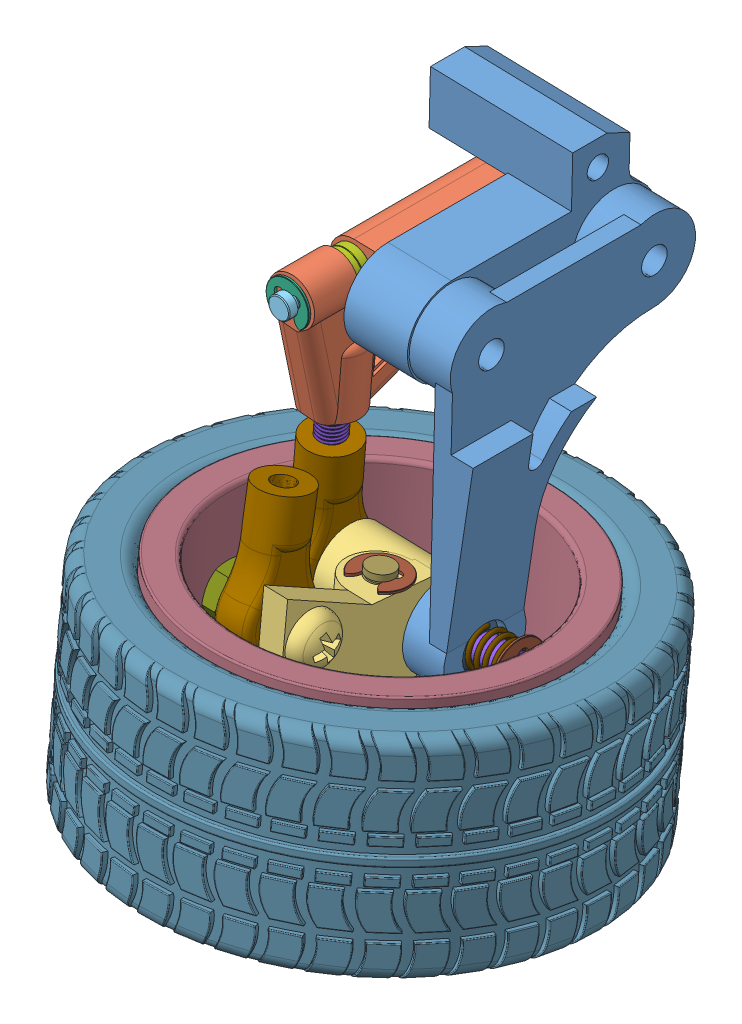
SolidWorks assembly 左前轮, configuration 默认. Lengths in mm.
35 component instances, 21 part files, 72 mates.
Components (placement in the parent):
- 前轮悬挂固定座-左-1: 前轮悬挂固定座-左 [默认] at (-4.1748 40.7369 44.8092) x (0 0 -1) z (-0.999668 0.025755 0) size (28.6 39.6 7.4)
- 前轮悬挂支撑臂-1: 前轮悬挂支撑臂 [默认] at (-19.3996 40.1041 44.6092) x (0 0 -1) z (-0.996802 0.079912 0) size (31.32 16.5 6)
- 转向摇臂-左-1: 转向摇臂-左 [默认] at (-10.8363 10.8664 44.7682) x (0.017235 0.996497 -0.081837) z (-0.999795 0.016302 -0.012048) size (14.2 22.2 10.13)
- 沉头螺钉-M3-1: 沉头螺钉-M3 [GB_WOOD_SCREWS_TYPE135 3X8-C] at (-13.5443 34.2761 39.8092) x (0.025755 0.999668 0) z (-0.463299 0.011936 0.886122) size (8.5 6 6)
- 沉头螺钉-M3-2: 沉头螺钉-M3 [GB_WOOD_SCREWS_TYPE135 3X8-C] at (-13.5443 34.2761 29.8092) x (0.025755 0.999668 0) z (0 0 1) size (8.5 6 6)
- 悬挂销钉-M2.5-1: 悬挂销钉-M2.5 [默认] at (-21.6922 40.2879 18.1092) size (2.5 2.5 34)
- 挡圈-M2.5-1: 挡圈-M2.5 [默认] at (-21.6922 40.2879 19.4092) x (-0.923728 -0.383049 0) z (0 0 -1) size (5 4.5 0.3)
- 挡圈-M2.5-2: 挡圈-M2.5 [默认] at (-21.6922 40.2879 50.8092) size (5 4.5 0.3)
- 垫片-M3-2: 垫片-M3 [默认] at (-21.6922 40.2879 43.4092) size (4.5 4.5 1)
- 垫片-M3-3: 垫片-M3 [默认] at (-21.6922 40.2879 44.4092) size (4.5 4.5 1)
- 垫片-M3-4: 垫片-M3 [默认] at (-21.6922 40.2879 25.1092) x (0.996807 -0.079852 0) z (0 0 1) size (4.5 4.5 1)
- 悬挂销钉-M3-1: 悬挂销钉-M3 [默认] at (-27.5329 11.1387 44.567) x (-0.007064 0.2769 0.960873) z (0.999795 -0.016302 0.012048) size (3 3 27.5)
- 前拉杆球头-1: 前拉杆球头 [默认] at (-24.0336 11.0816 44.6092) x (-0.079912 -0.996802 0) z (0 0 1) size (16.5 5.82 9)
- 半球型活动头-1: 半球型活动头 [默认] at (-24.0567 11.7504 47.4309) x (0.007965 -0.230623 -0.973011) z (-0.018641 -0.972907 0.230446) size (5.8 4.8 5.8)
- 挡圈-M3-1: 挡圈-M3 [默认] at (-26.7331 11.1256 44.5767) x (0.019643 0.925969 -0.377089) z (0.999795 -0.016302 0.012048) size (6 5.32 0.3)
- 挡圈-M3-2: 挡圈-M3 [默认] at (-1.1383 10.7083 44.8851) x (0.019537 0.616444 -0.787156) z (0.999795 -0.016302 0.012048) size (6 5.32 0.3)
- 垫片-M3-5: 垫片-M3 [默认] at (-20.6343 11.0262 44.6501) x (-0.007721 0.243313 0.969917) z (-0.999795 0.016302 -0.012048) size (4.5 4.5 1)
- 半球型活动头-2: 半球型活动头 [默认] at (-7.4714 10.8468 47.7088) x (0.011847 -0.012367 -0.999853) z (0.016449 0.999791 -0.012172) size (5.8 4.8 5.8)
- 垫片-M3-6: 垫片-M3 [默认] at (-9.8366 10.8501 44.7803) x (-0.014725 -0.175564 0.984358) z (-0.999795 0.016302 -0.012048) size (4.5 4.5 1)
- 前轮轴-1: 前轮轴 [默认] at (-13.6492 12.9342 48.5817) x (-0.911466 0.049305 0.408411) z (0.017235 0.996497 -0.081837) size (4.6 4.19 25.74)
- 挡圈-M3-3: 挡圈-M3 [默认] at (-13.6043 15.5251 48.3689) x (0.998548 -0.021333 -0.049473) z (0.017235 0.996497 -0.081837) size (6 5.32 0.3)
- 轮毂-前轮-1: 轮毂-前轮 [默认] at (-14.0076 -7.7929 50.2839) x (0.552508 -0.077709 -0.829877) z (0.833329 0.030913 0.551912) size (40 26.36 40)
- 橡胶胎-1: 橡胶胎 [默认] at (-14.0111 -7.9922 50.3002) x (0.552508 -0.077709 -0.829877) z (0.833329 0.030913 0.551912) size (52.2 24.12 52.2)
- 深沟轴承-M7-1: 深沟轴承-M7 [Rolling bearings 618-3 GB 276-94] at (-13.8215 2.9692 49.4) x (-0.017235 -0.996497 0.081837) z (0.158761 0.078083 0.984224) size (2 7 7)
- 深沟轴承-M7-2: 深沟轴承-M7 [Rolling bearings 618-3 GB 276-94] at (-13.9594 -5.0027 50.0547) x (0.017235 0.996497 -0.081837) z (0.833329 0.030913 0.551912) size (2 7 7)
- 六角螺母-M3-2: 六角螺母-M3 [GB_FASTENER_NUT_SNAB1 M3-C] at (-13.9766 -5.9992 50.1366) x (0.998548 -0.021333 -0.049473) z (0.017235 0.996497 -0.081837) size (6.35 5.5 2.4)
- 丝杆-1: 丝杆 [默认] at (-22.3555 32.0144 44.6092) x (0.307617 -0.024661 0.951191) z (0.079912 0.996802 0) size (3.03 3.46 12.09)
- 弹簧-1: 弹簧 [默认] at (-1.1383 10.7083 44.8851) x (0.019001 0.96076 -0.276728) z (0.999795 -0.016302 0.012048) size (4.64 4.5 4.5)
- 前轮悬挂连接件下半部分-左-2: 前轮悬挂连接件下半部分-左 [默认] at (-8.9732 40.8605 44.8092) x (0.025755 0.999668 0) z (-0.999668 0.025755 0) size (16 29 16.6)
- 前轮悬挂连接件上半部分-左-3: 前轮悬挂连接件上半部分-左 [默认] at (-21.6922 40.2879 26.2092) x (0.999668 -0.025755 0) z (0 0 1) size (14.6 8.6 17.2)
- 垫片-M3-7: 垫片-M3 [默认] at (-21.6922 40.2879 24.1092) size (4.5 4.5 1)
- 前拉杆球头-2: 前拉杆球头 [默认] at (-16.1263 16.0335 59.1372) x (0.028951 -0.979751 0.198115) z (-0.030341 0.197245 0.979885) size (16.5 5.82 9)
- 半球型活动头-3: 半球型活动头 [默认] at (-16.0795 18.9329 59.1727) x (-0.016155 -0.999795 -0.012245) z (-0.012245 -0.012048 0.999852) size (5.8 4.8 5.8)
- 六角螺母-M3-3: 六角螺母-M3 [GB_FASTENER_NUT_SNAB1 M3-C] at (-18.5258 16.0726 59.1082) x (0.012311 0.016105 -0.999795) z (0.999795 -0.016302 0.012048) size (6.35 5.5 2.4)
- 十字半圆头长螺钉-M3-1: 十字半圆头长螺钉-M3 [GB_WOOD_SCREWS_TYPE136 M3X8-N] at (-8.5579 15.9101 59.2284) x (-0.999795 0.016302 -0.012048) z (0.012048 0.955859 0.293578) size (12.81 5.8 5.8)
Mates (geometry in assembly coordinates):
- 同心6: concentric anti-aligned: cylinder of 前轮悬挂支撑臂-1 through (-21.6922 40.2879 19.4092) axis (0 0 1) radius 1.25; cylinder of 悬挂销钉-M2.5-1 through (-21.6922 40.2879 52.1092) axis (0 0 -1) radius 1.25
- 重合8: coincident anti-aligned: plane of 挡圈-M2.5-1 through (-21.3853 40.7443 19.1092) normal (0 0 -1); plane of 悬挂销钉-M2.5-1 through (-21.6922 40.2879 19.1092) normal (0 0 1)
- 同心7: concentric anti-aligned: cylinder of 悬挂销钉-M2.5-1 through (-21.6922 40.2879 52.1092) axis (0 0 -1) radius 1.25; cylinder of 挡圈-M2.5-1 through (-21.6922 40.2879 19.1092) axis (0 0 1) radius 1.1
- 重合9: coincident anti-aligned: plane of 前轮悬挂支撑臂-1 through (-24.3285 36.1854 19.4092) normal (0 0 -1); plane of 挡圈-M2.5-1 through (-21.3853 40.7443 19.4092) normal (0 0 1)
- 同心8: concentric aligned: cylinder of 悬挂销钉-M2.5-1 through (-21.6922 40.2879 52.1092) axis (0 0 -1) radius 1.25; cylinder of 挡圈-M2.5-2 through (-21.6922 40.2879 51.1092) axis (0 0 -1) radius 1.1
- 重合10: coincident anti-aligned: plane of 悬挂销钉-M2.5-1 through (-21.6922 40.2879 51.1092) normal (0 0 -1); plane of 挡圈-M2.5-2 through (-22.1505 40.5919 51.1092) normal (0 0 1)
- 同心9: concentric aligned: cylinder of 悬挂销钉-M2.5-1 through (-21.6922 40.2879 52.1092) axis (0 0 -1) radius 1.25; cylinder of 垫片-M3-4 through (-21.6922 40.2879 26.1092) axis (0 0 -1) radius 1.5
- 同心10: concentric aligned: cylinder of 垫片-M3-2 through (-21.6922 40.2879 44.4092) axis (0 0 -1) radius 1.5; cylinder of 垫片-M3-3 through (-21.6922 40.2879 45.4092) axis (0 0 -1) radius 1.5
- 重合12: coincident anti-aligned: plane of 垫片-M3-2 through (-21.6922 40.2879 44.4092) normal (0 0 1); plane of 垫片-M3-3 through (-21.6922 40.2879 44.4092) normal (0 0 -1)
- 同心11: concentric aligned: cylinder of 悬挂销钉-M2.5-1 through (-21.6922 40.2879 52.1092) axis (0 0 -1) radius 1.25; cylinder of 垫片-M3-3 through (-21.6922 40.2879 45.4092) axis (0 0 -1) radius 1.5
- 重合13: coincident anti-aligned: plane of 前轮悬挂支撑臂-1 through (-23.7691 43.1631 45.4092) normal (0 0 -1); plane of 垫片-M3-3 through (-21.6922 40.2879 45.4092) normal (0 0 1)
- 同心12: concentric anti-aligned: cylinder of 前轮悬挂支撑臂-1 through (-22.795 26.532 44.6092) axis (-0.079912 -0.996802 0) radius 1.25; cylinder of 前拉杆球头-1 through (-23.0747 23.0432 44.6092) axis (0.079912 0.996802 0) radius 1.25
- 平行3: parallel aligned: plane of 前轮悬挂支撑臂-1 through (-23.9848 40.4717 44.6092) normal (-0.996802 0.079912 0); plane of 前拉杆球头-1 through (-26.5862 6.7718 40.6836) normal (-0.996802 0.079912 0)
- 同心15: concentric: sphere of 前拉杆球头-1; sphere of 半球型活动头-1
- 距离2: distance = 3.5 mm anti-aligned: plane of 前拉杆球头-1 through (-23.0747 23.0432 44.6092) normal (0.079912 0.996802 0); plane of 前轮悬挂支撑臂-1 through (-25.0876 26.7158 47.6092) normal (-0.079912 -0.996802 0)
- 同心16: concentric anti-aligned: cylinder of 悬挂销钉-M3-1 through (-0.0386 10.6903 44.8983) axis (-0.999795 0.016302 -0.012048) radius 1.5; cylinder of 半球型活动头-1 through (-26.4331 11.1207 44.5803) axis (0.999795 -0.016302 0.012048) radius 1.5
- 同心17: concentric aligned: cylinder of 悬挂销钉-M3-1 through (-26.3332 11.1191 44.5815) axis (-0.999795 0.016302 -0.012048) radius 1.25; cylinder of 挡圈-M3-1 through (-26.4331 11.1207 44.5803) axis (-0.999795 0.016302 -0.012048) radius 1.3
- 重合17: coincident anti-aligned: plane of 悬挂销钉-M3-1 through (-26.7331 11.1256 44.5767) normal (0.999795 -0.016302 0.012048); plane of 挡圈-M3-1 through (-26.7455 10.7596 45.1137) normal (-0.999795 0.016302 -0.012048)
- 同心18: concentric anti-aligned: cylinder of 悬挂销钉-M3-1 through (-1.1383 10.7083 44.8851) axis (0.999795 -0.016302 0.012048) radius 1.25; cylinder of 挡圈-M3-2 through (-0.8384 10.7034 44.8887) axis (-0.999795 0.016302 -0.012048) radius 1.3
- 重合18: coincident anti-aligned: plane of 悬挂销钉-M3-1 through (-0.8384 10.7034 44.8887) normal (-0.999795 0.016302 -0.012048); plane of 挡圈-M3-2 through (-0.847 10.6523 45.5366) normal (0.999795 -0.016302 0.012048)
- 重合19: coincident anti-aligned: plane of 半球型活动头-1 through (-26.3529 16.3607 45.012) normal (-0.999795 0.016302 -0.012048); plane of 挡圈-M3-1 through (-26.4456 10.7547 45.1173) normal (0.999795 -0.016302 0.012048)
- 同心19: concentric anti-aligned: cylinder of 转向摇臂-左-1 through (-13.6358 10.9121 44.7345) axis (0.999795 -0.016302 0.012048) radius 1.5; cylinder of 悬挂销钉-M3-1 through (-0.0386 10.6903 44.8983) axis (-0.999795 0.016302 -0.012048) radius 1.5
- 同心20: concentric anti-aligned: cylinder of 悬挂销钉-M3-1 through (-0.0386 10.6903 44.8983) axis (-0.999795 0.016302 -0.012048) radius 1.5; cylinder of 垫片-M3-5 through (-21.6341 11.0425 44.6381) axis (0.999795 -0.016302 0.012048) radius 1.5
- 重合21: coincident anti-aligned: plane of 转向摇臂-左-1 through (-20.6343 11.0262 44.6501) normal (-0.999795 0.016302 -0.012048); plane of 垫片-M3-5 through (-20.6343 11.0262 44.6501) normal (0.999795 -0.016302 0.012048)
- 同心21: concentric aligned: cylinder of 悬挂销钉-M3-1 through (-0.0386 10.6903 44.8983) axis (-0.999795 0.016302 -0.012048) radius 1.5; cylinder of 半球型活动头-2 through (-5.0375 10.7719 44.8381) axis (-0.999795 0.016302 -0.012048) radius 1.5
- 同心22: concentric: sphere of 前轮悬挂固定座-左-1; sphere of 半球型活动头-2
- 同心28: concentric anti-aligned: cylinder of 悬挂销钉-M3-1 through (-0.0386 10.6903 44.8983) axis (-0.999795 0.016302 -0.012048) radius 1.5; cylinder of 垫片-M3-6 through (-10.8363 10.8664 44.7682) axis (0.999795 -0.016302 0.012048) radius 1.5
- 重合24: coincident anti-aligned: plane of 半球型活动头-2 through (-9.9381 5.8713 46.4688) normal (-0.999795 0.016302 -0.012048); plane of 垫片-M3-6 through (-9.8366 10.8501 44.7803) normal (0.999795 -0.016302 0.012048)
- 重合25: coincident anti-aligned: plane of 转向摇臂-左-1 through (-10.8363 10.8664 44.7682) normal (0.999795 -0.016302 0.012048); plane of 垫片-M3-6 through (-10.8363 10.8664 44.7682) normal (-0.999795 0.016302 -0.012048)
- 重合26: coincident anti-aligned: plane of 半球型活动头-1 through (-21.5539 16.2824 45.0698) normal (0.999795 -0.016302 0.012048); plane of 垫片-M3-5 through (-21.6341 11.0425 44.6381) normal (-0.999795 0.016302 -0.012048)
- 同心29: concentric anti-aligned: cylinder of 转向摇臂-左-1 through (-13.7698 5.9587 49.1545) axis (0.017235 0.996497 -0.081837) radius 1.5; cylinder of 前轮轴-1 through (-13.5871 16.5216 48.287) axis (-0.017235 -0.996497 0.081837) radius 1.5
- 重合27: coincident anti-aligned: plane of 转向摇臂-左-1 through (-13.6245 12.7448 46.2802) normal (-0.509139 0.079189 0.857033); plane of 前轮轴-1 through (-13.7796 3.7763 47.0167) normal (0.509139 -0.079189 -0.857033)
- 重合28: coincident anti-aligned: plane of 转向摇臂-左-1 through (-10.807 12.5605 44.6291) normal (-0.017235 -0.996497 0.081837); plane of 前轮轴-1 through (-13.6492 12.9342 48.5817) normal (0.017235 0.996497 -0.081837)
- 重合29: coincident anti-aligned: plane of 前轮轴-1 through (-13.5992 15.8241 48.3443) normal (-0.017235 -0.996497 0.081837); plane of 挡圈-M3-3 through (-14.1584 15.8066 48.0135) normal (0.017235 0.996497 -0.081837)
- 同心31: concentric aligned: cylinder of 前轮轴-1 through (-13.5871 16.5216 48.287) axis (-0.017235 -0.996497 0.081837) radius 1.5; cylinder of 挡圈-M3-3 through (-13.5992 15.8241 48.3443) axis (-0.017235 -0.996497 0.081837) radius 1.3
- 同心32: concentric aligned: cylinder of 轮毂-前轮-1 through (-14.0076 -7.7929 50.2839) axis (-0.017235 -0.996497 0.081837) radius 18; cylinder of 橡胶胎-1 through (-14.0076 -7.7929 50.2839) axis (-0.017235 -0.996497 0.081837) radius 20
- 重合30: coincident aligned: plane of 轮毂-前轮-1 through (-24.9473 -6.2543 66.7154) normal (-0.017235 -0.996497 0.081837); plane of 橡胶胎-1 through (-28.0966 -5.8113 71.4457) normal (-0.017235 -0.996497 0.081837)
- 同心331: concentric aligned: cylinder of 前轮轴-1 through (-14.0283 -8.9887 50.3821) axis (0.017235 0.996497 -0.081837) radius 1.5; cylinder of 深沟轴承-M7-1 through (-13.7014 9.9162 48.8295) axis (0.017235 0.996497 -0.081837) radius 1.5
- 同心34: concentric anti-aligned: cylinder of 深沟轴承-M7-1 through (-13.6714 11.6494 48.6872) axis (0.017235 0.996497 -0.081837) radius 3.5; cylinder of 轮毂-前轮-1 through (-14.0076 -7.7929 50.2839) axis (-0.017235 -0.996497 0.081837) radius 2
- 重合31: coincident anti-aligned: plane of 轮毂-前轮-1 through (-13.8387 1.9727 49.4819) normal (0.017235 0.996497 -0.081837); plane of 深沟轴承-M7-1 through (-10.3837 1.8679 48.9329) normal (-0.017235 -0.996497 0.081837)
- 同心35: concentric aligned: cylinder of 轮毂-前轮-1 through (-13.9422 -4.0062 49.9729) axis (-0.017235 -0.996497 0.081837) radius 3.5; cylinder of 深沟轴承-M7-2 through (-14.1095 -13.6829 50.7676) axis (-0.017235 -0.996497 0.081837) radius 3.5
- 重合32: coincident anti-aligned: plane of 轮毂-前轮-1 through (-13.9422 -4.0062 49.9729) normal (-0.017235 -0.996497 0.081837); plane of 深沟轴承-M7-2 through (-15.8759 -3.7343 52.8775) normal (0.017235 0.996497 -0.081837)
- 重合33: coincident anti-aligned: plane of 前轮轴-1 through (-13.8043 3.9657 49.3182) normal (-0.017235 -0.996497 0.081837); plane of 深沟轴承-M7-1 through (-11.6654 3.9008 48.9783) normal (0.017235 0.996497 -0.081837)
- 重合34: coincident aligned: plane of 轮毂-前轮-1 through (-14.0076 -7.7929 50.2839) normal (0.833329 0.030913 0.551912); plane of 橡胶胎-1 through (-14.0111 -7.9922 50.3002) normal (0.833329 0.030913 0.551912)
- 重合35: coincident aligned: plane of 橡胶胎-1 through (-14.0111 -7.9922 50.3002) normal (0.833329 0.030913 0.551912); plane of 深沟轴承-M7-2 through (-13.9594 -5.0027 50.0547) normal (0.833329 0.030913 0.551912)
- 同心36: concentric anti-aligned: cylinder of 深沟轴承-M7-2 through (-14.0795 -11.9497 50.6252) axis (-0.017235 -0.996497 0.081837) radius 2.1667; cylinder of 六角螺母-M3-2 through (-14.018 -8.3908 50.333) axis (0.017235 0.996497 -0.081837) radius 1.2295
- 重合36: coincident anti-aligned: plane of 深沟轴承-M7-2 through (-15.1737 -5.8309 51.9346) normal (-0.017235 -0.996497 0.081837); plane of 六角螺母-M3-2 through (-10.8058 -6.067 49.9795) normal (0.017235 0.996497 -0.081837)
- 同心37: concentric anti-aligned: cylinder of 前拉杆球头-1 through (-23.0747 23.0432 44.6092) axis (0.079912 0.996802 0) radius 1.25; cylinder of 丝杆-1 through (-22.3555 32.0144 44.6092) axis (-0.079912 -0.996802 0) radius 1.2957
- 距离4: distance = 3 mm anti-aligned: plane of 丝杆-1 through (-23.3144 20.0528 44.6092) normal (-0.079912 -0.996802 0); plane of 前拉杆球头-1 through (-23.0747 23.0432 44.6092) normal (0.079912 0.996802 0)
- 重合39: coincident anti-aligned: plane of 挡圈-M3-2 through (-1.147 10.6572 45.533) normal (-0.999795 0.016302 -0.012048); plane of 弹簧-1 through (-1.1625 8.0593 43.3067) normal (0.999795 -0.016302 0.012048)
- 重合40: coincident aligned: plane of 悬挂销钉-M3-1; plane of 弹簧-1
- 重合43: coincident anti-aligned: plane of 悬挂销钉-M3-1; plane of 弹簧-1
- 重合45: coincident anti-aligned: plane of 前轮悬挂固定座-左-1 through (-9.7459 10.8705 44.8092) normal (-0.999668 0.025755 0); plane of 前轮悬挂连接件下半部分-左-2 through (-8.9732 40.8605 25.8092) normal (0.999668 -0.025755 0)
- 同心332: concentric anti-aligned: cylinder of 前轮悬挂固定座-左-1 through (-6.1742 40.7884 25.8092) axis (0.999668 -0.025755 0) radius 1.5; cylinder of 前轮悬挂连接件下半部分-左-2 through (-16.3708 41.0511 25.8092) axis (-0.999668 0.025755 0) radius 1.25
- 同心333: concentric anti-aligned: cylinder of 前轮悬挂固定座-左-1 through (-6.1742 40.7884 44.8092) axis (0.999668 -0.025755 0) radius 1.5; cylinder of 前轮悬挂连接件下半部分-左-2 through (-16.3708 41.0511 44.8092) axis (-0.999668 0.025755 0) radius 1.25
- 同心334: concentric aligned: cylinder of 悬挂销钉-M2.5-1 through (-21.6922 40.2879 52.1092) axis (0 0 -1) radius 1.25; cylinder of 前轮悬挂连接件上半部分-左-3 through (-21.6922 40.2879 43.4092) axis (0 0 -1) radius 1.25
- 重合46: coincident anti-aligned: plane of 垫片-M3-2 through (-21.6922 40.2879 43.4092) normal (0 0 -1); plane of 前轮悬挂连接件上半部分-左-3 through (-21.8774 33.1012 43.4092) normal (0 0 1)
- 重合49: coincident anti-aligned: plane of 前轮悬挂连接件下半部分-左-2 through (-16.3708 41.0511 25.8092) normal (-0.999668 0.025755 0); plane of 前轮悬挂连接件上半部分-左-3 through (-16.3244 42.8505 43.4092) normal (0.999668 -0.025755 0)
- 重合50: coincident anti-aligned: plane of 前轮悬挂连接件下半部分-左-2 through (-16.4532 37.8522 25.8092) normal (-0.025755 -0.999668 0); plane of 前轮悬挂连接件上半部分-左-3 through (-16.4532 37.8522 43.4092) normal (0.025755 0.999668 0)
- 同心336: concentric aligned: cylinder of 前轮悬挂连接件下半部分-左-2 through (-13.4542 37.7749 29.8092) axis (-0.025755 -0.999668 0) radius 1.25; cylinder of 前轮悬挂连接件上半部分-左-3 through (-13.5469 34.1761 29.8092) axis (-0.025755 -0.999668 0) radius 1.7
- 重合51: coincident aligned: cone of 沉头螺钉-M3-2 through (-13.5005 35.9755 29.8092) axis (0.025755 0.999668 0); cone of 前轮悬挂连接件上半部分-左-3 through (-13.5469 34.1761 29.8092) axis (0.025755 0.999668 0)
- 重合52: coincident aligned: cone of 沉头螺钉-M3-1 through (-13.5005 35.9755 39.8092) axis (0.025755 0.999668 0); cone of 前轮悬挂连接件上半部分-左-3 through (-13.5469 34.1761 39.8092) axis (0.025755 0.999668 0)
- 重合53: coincident anti-aligned: plane of 垫片-M3-4 through (-21.6922 40.2879 25.1092) normal (0 0 -1); plane of 垫片-M3-7 through (-21.6922 40.2879 25.1092) normal (0 0 1)
- 同心337: concentric aligned: cylinder of 悬挂销钉-M2.5-1 through (-21.6922 40.2879 52.1092) axis (0 0 -1) radius 1.25; cylinder of 垫片-M3-7 through (-21.6922 40.2879 25.1092) axis (0 0 -1) radius 1.5
- 距离5: distance = 0.1 mm anti-aligned: plane of 前轮悬挂支撑臂-1 through (-24.2486 37.1822 24.0092) normal (0 0 1); plane of 垫片-M3-7 through (-21.6922 40.2879 24.1092) normal (0 0 -1)
- 重合55: coincident anti-aligned: plane of 转向摇臂-左-1 through (-13.6358 10.9121 44.7345) normal (-0.999795 0.016302 -0.012048); plane of 半球型活动头-3 through (-13.6393 17.6822 54.1868) normal (0.999795 -0.016302 0.012048)
- 同心3411: concentric aligned: cylinder of 转向摇臂-左-1 through (-13.7268 15.9944 59.1661) axis (0.999795 -0.016302 0.012048) radius 1.5; cylinder of 十字半圆头长螺钉-M3-1 through (5.0686 15.6879 59.3926) axis (0.999795 -0.016302 0.012048) radius 1.5
- 重合561: coincident anti-aligned: plane of 转向摇臂-左-1 through (-10.8363 10.8664 44.7682) normal (0.999795 -0.016302 0.012048); plane of 十字半圆头长螺钉-M3-1 through (-10.9455 14.5149 58.7594) normal (-0.999795 0.016302 -0.012048)
- 重合57: coincident anti-aligned: plane of 半球型活动头-3 through (-18.4383 17.7604 54.1289) normal (-0.999795 0.016302 -0.012048); plane of 六角螺母-M3-3 through (-18.4867 16.1238 55.9335) normal (0.999795 -0.016302 0.012048)
- 同心342: concentric anti-aligned: cylinder of 六角螺母-M3-3 through (-20.9253 16.1117 59.0793) axis (0.999795 -0.016302 0.012048) radius 1.2295; cone of 十字半圆头长螺钉-M3-1 through (-19.4256 16.0873 59.0974) axis (-0.999795 0.016302 -0.012048)
- 同心343: concentric: sphere of 前拉杆球头-2; sphere of 半球型活动头-3
- 同心344: concentric aligned: cylinder of 半球型活动头-3 through (-18.5258 16.0726 59.1082) axis (0.999795 -0.016302 0.012048) radius 1.5; cylinder of 十字半圆头长螺钉-M3-1 through (5.0686 15.6879 59.3926) axis (0.999795 -0.016302 0.012048) radius 1.5
